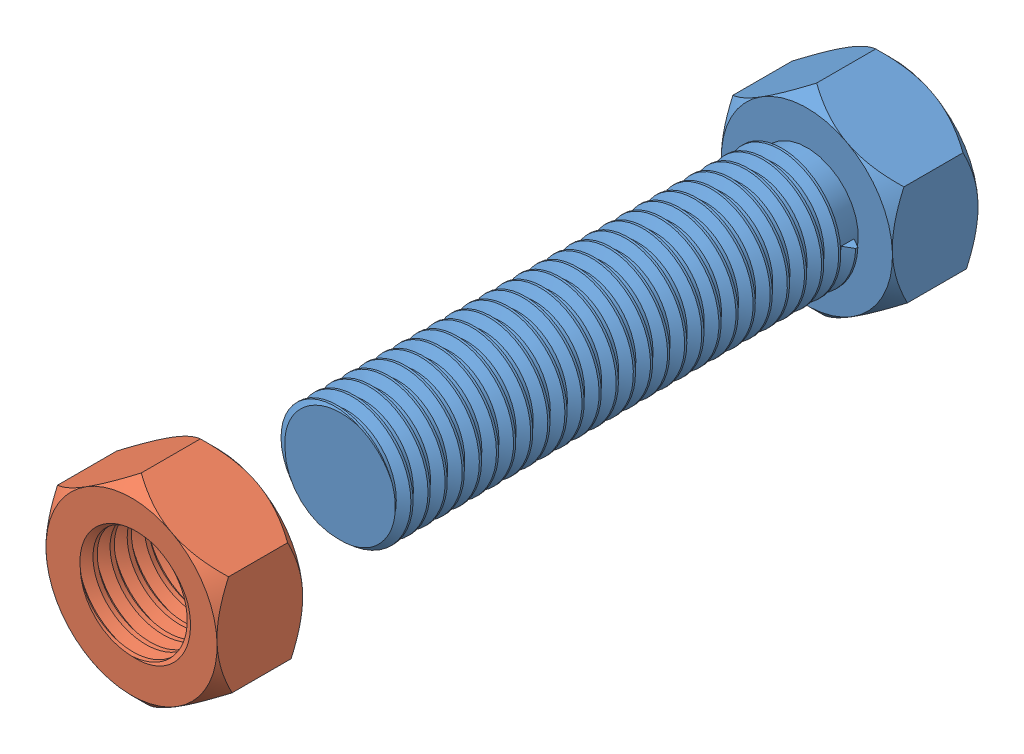
SolidWorks assembly Assem4, configuration Default. Lengths in mm.
Overall size (11.35 11.54 44.81).
3 component instances, 3 part files, 9 mates.
Components (placement in the parent):
- Assembly lab 1 bolt-1: Assembly lab 1 bolt [Default] at (13.477 23.173 20.6438) size (11.35 11.54 32.98)
- Part3^Assem4-1: Part3^Assem4 [Default] at origin (virtual)
- Assembly lab 1 nut-8: Assembly lab 1 nut [Default] at (13.477 23.173 60.1127) size (11.35 11.54 5.69)
Mates (geometry in assembly coordinates):
- Tangent1: tangent: curve of Assembly lab 1 bolt-1; edge_curve of ?
- Concentric4: concentric aligned: circle of Assembly lab 1 bolt-1; circle of Assembly lab 1 nut-4
- Linear/Linear Coupler1: linear coupler = 1 : 28 mm: plane of Assembly lab 1 bolt-1 through (13.477 23.173 23.1438) normal (0 0 1); plane of Assembly lab 1 nut-4 through (13.477 23.173 33.0096) normal (0 0 1)
- Concentric5: concentric aligned: circle of Assembly lab 1 bolt-1; circle of Assembly lab 1 nut-6
- LimitDistance2: limit distance = 28.1931 mm aligned: plane of Assembly lab 1 bolt-1 through (13.477 23.173 23.1438) normal (0 0 1); plane of Assembly lab 1 nut-6 through (13.477 23.173 51.3368) normal (0 0 1)
- LimitDistance3: limit distance = 28.1931 mm aligned: plane of Assembly lab 1 nut-6 through (13.477 23.173 51.3368) normal (0 0 1); plane of Assembly lab 1 bolt-1 through (13.477 23.173 23.1438) normal (0 0 1)
- Concentric6: concentric anti-aligned: cylinder of Assembly lab 1 bolt-1 through (13.477 23.173 50.6438) axis (0 0 -1) radius 3; cylinder of Assembly lab 1 nut-6 through (13.477 23.173 25.3368) axis (0 0 1) radius 3
- LimitDistance5: limit distance = 28.1931 mm aligned: plane of Assembly lab 1 bolt-1 through (13.477 23.173 23.1438) normal (0 0 1); plane of Assembly lab 1 nut-6 through (13.477 23.173 51.3368) normal (0 0 1)
- Concentric8: concentric aligned: circle of Assembly lab 1 bolt-1; circle of Assembly lab 1 nut-8
